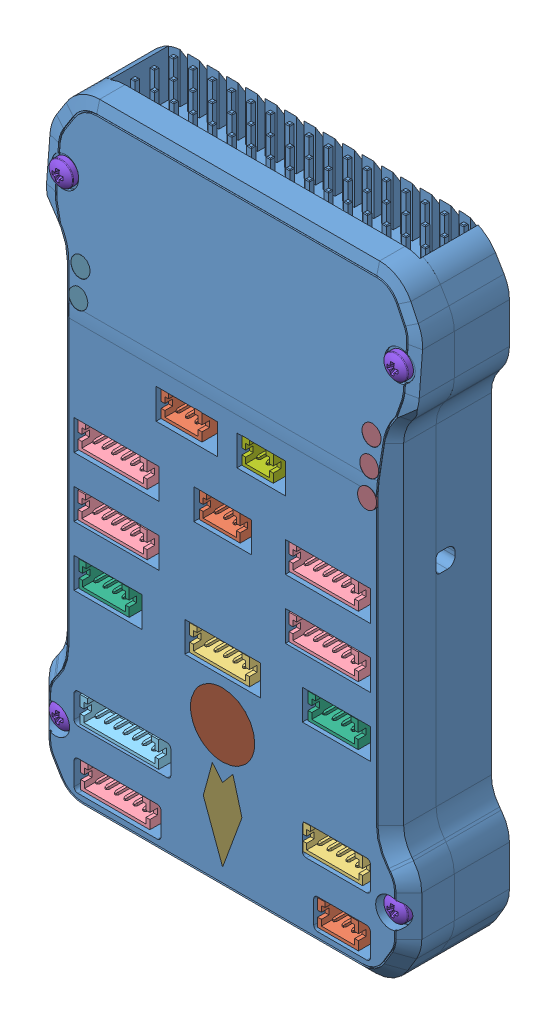
SolidWorks assembly Pixhawk, configuration Défaut. Lengths in mm.
Overall size (49.31 81.3 15.24).
26 component instances, 14 part files, 57 mates.
Components (placement in the parent):
- Pixhawk APM-1: Pixhawk APM [Défaut] at (-24.9203 -39.4022 0) size (49.31 81.3 15.03)
- DF13-3P-1.25DSA-1: DF13-3P-1.25DSA [Défaut] at (0.001 -60.127 12.2305) x (0 -1 0) z (-1 0 0) size (3.4 6.6 5.4)
- DF13-5P-1.25DSA-1: DF13-5P-1.25DSA [Défaut] at (0.5502 -52.3839 12.2305) x (0 -1 0) z (-1 0 0) size (3.4 6.6 7.9)
- DF13-6P-1.25DSA-1: DF13-6P-1.25DSA [Défaut] at (-27.5951 -60.0382 12.2305) x (0 -1 0) z (-1 0 0) size (3.4 6.6 9.15)
- DF13-7P-1.25DSA-1: DF13-7P-1.25DSA [Défaut] at (-26.4213 -52.538 12.2305) x (0 -1 0) z (-1 0 0) size (3.4 6.6 10.4)
- DF13-4P-1.25DSA-1: DF13-4P-1.25DSA [Défaut] at (-0.0265 -37.0823 12.2305) x (0 -1 0) z (-1 0 0) size (3.4 6.6 6.65)
- DF13-4P-1.25DSA-2: DF13-4P-1.25DSA [Défaut] at (-30.3382 -37.0823 12.2305) x (0 -1 0) z (-1 0 0) size (3.4 6.6 6.65)
- DF13-5P-1.25DSA-2: DF13-5P-1.25DSA [Défaut] at (-14.4216 -37.0823 12.2305) x (0 -1 0) z (-1 0 0) size (3.4 6.6 7.9)
- DF13-6P-1.25DSA-2: DF13-6P-1.25DSA [Défaut] at (-0.012 -29.2904 12.2305) x (0 -1 0) z (-1 0 0) size (3.4 6.6 9.15)
- DF13-6P-1.25DSA-3: DF13-6P-1.25DSA [Défaut] at (-0.012 -21.2194 12.2305) x (0 -1 0) z (-1 0 0) size (3.4 6.6 9.15)
- DF13-6P-1.25DSA-4: DF13-6P-1.25DSA [Défaut] at (-27.948 -29.2904 12.2305) x (0 -1 0) z (-1 0 0) size (3.4 6.6 9.15)
- DF13-6P-1.25DSA-5: DF13-6P-1.25DSA [Défaut] at (-27.948 -21.2194 12.2305) x (0 -1 0) z (-1 0 0) size (3.4 6.6 9.15)
- DF13-3P-1.25DSA-2: DF13-3P-1.25DSA [Défaut] at (-15.6441 -21.2194 12.2305) x (0 -1 0) z (-1 0 0) size (3.4 6.6 5.4)
- DF13-2P-1.25DSA-1: DF13-2P-1.25DSA [Défaut] at (-11.2684 -12.1811 12.2305) x (0 -1 0) z (-1 0 0) size (3.4 6.6 4.15)
- DF13-3P-1.25DSA-3: DF13-3P-1.25DSA [Défaut] at (-20.7011 -12.1811 12.2305) x (0 -1 0) z (-1 0 0) size (3.4 6.6 5.4)
- pan head cross recess screw_iso-1: pan head cross recess screw_iso [ISO 7045 - M1.6 x 3 - Z --- 3N] at (21.8797 32.2978 14.8) x (0 0 -1) z (1 0 0) size (4.27 3.2 3.2)
- pan head cross recess screw_iso-2: pan head cross recess screw_iso [ISO 7045 - M1.6 x 3 - Z --- 3N] at (-22.4203 32.2978 14.8) x (0 0 -1) z (1 0 0) size (4.27 3.2 3.2)
- pan head cross recess screw_iso-3: pan head cross recess screw_iso [ISO 7045 - M1.6 x 3 - Z --- 3N] at (21.8797 -29.8022 14.8) x (0 0 -1) z (1 0 0) size (4.27 3.2 3.2)
- pan head cross recess screw_iso-4: pan head cross recess screw_iso [ISO 7045 - M1.6 x 3 - Z --- 3N] at (-22.4203 -29.8022 14.8) x (0 0 -1) z (1 0 0) size (4.27 3.2 3.2)
- micro USB-2: micro USB [Défaut] at (-38.5288 4.0262 13.8589) x (0 1 0) z (-1 0 0) size (7.99 2.94 5.43)
  - micro usb02-1: micro usb02 [Défaut] at (-14.4796 6.4719 -20.7085) size (6.9 2.16 4.2)
  - micro USB-1: micro USB [Défaut] at (-14.4796 6.4719 -16.0085) size (7.99 2.94 5.43)
- pièce10^Pixhawk-1: pièce10^Pixhawk [Défaut] at (-24.9203 -39.4022 14.5) size (8.5 8.5 0.5) (virtual)
- pièce11^Pixhawk-1: pièce11^Pixhawk [Défaut] at (-24.9203 -39.4022 14.5) size (5.12 11.31 0.5) (virtual)
- Pièce12^Pixhawk-1: Pièce12^Pixhawk [Défaut] at (-24.9203 -37.8072 19.1403) x (1 0 0) z (0 0.083045 0.996546) size (2.5 9.53 0.5) (virtual)
- Pièce13^Pixhawk-1: Pièce13^Pixhawk [Défaut] at (-24.9203 -37.8072 19.1403) x (1 0 0) z (0 0.083045 0.996546) size (2.5 6.02 0.5) (virtual)
Mates (geometry in assembly coordinates):
- Coïncidente1: coincident aligned: plane of Pixhawk APM-1 through (-24.9203 -39.4022 15) normal (0 0 1); plane of DF13-3P-1.25DSA-1 through (18.451 -36.0098 15) normal (0 0 1)
- Parallèle1: parallel anti-aligned: plane of Pixhawk APM-1 through (19.2797 -36.8022 10) normal (0 1 0); plane of DF13-3P-1.25DSA-1 through (2.1962 -36.3098 14.6158) normal (0 -1 0)
- Coïncidente2: coincident aligned: plane of Pixhawk APM-1 through (-24.9203 -39.4022 15) normal (0 0 1); plane of DF13-5P-1.25DSA-1 through (10.8502 -25.8167 15) normal (0 0 1)
- Parallèle2: parallel anti-aligned: plane of Pixhawk APM-1 through (19.2797 -29.1022 10) normal (0 1 0); plane of DF13-5P-1.25DSA-1 through (15.2454 -28.5667 14.6158) normal (0 -1 0)
- Coïncidente4: coincident aligned: plane of Pixhawk APM-1 through (-24.9203 -39.4022 15) normal (0 0 1); plane of DF13-6P-1.25DSA-1 through (-18.5451 -33.471 15) normal (0 0 1)
- Parallèle3: parallel anti-aligned: plane of Pixhawk APM-1 through (-8.4203 -36.8022 10) normal (0 1 0); plane of DF13-6P-1.25DSA-1 through (-14.1499 -36.221 14.6158) normal (0 -1 0)
- Coïncidente5: coincident aligned: plane of Pixhawk APM-1 through (-24.9203 -39.4022 15) normal (0 0 1); plane of DF13-7P-1.25DSA-1 through (-22.9713 -28.4208 15) normal (0 0 1)
- Parallèle5: parallel anti-aligned: plane of Pixhawk APM-1 through (-7.1203 -29.1022 10) normal (0 1 0); plane of DF13-7P-1.25DSA-1 through (-24.2261 -28.7208 14.6158) normal (0 -1 0)
- Coïncidente6: coincident aligned: plane of Pixhawk APM-1 through (-24.9203 -39.4022 15) normal (0 0 1); plane of DF13-4P-1.25DSA-2 through (-26.8882 -12.9652 15) normal (0 0 1)
- Parallèle6: parallel anti-aligned: plane of Pixhawk APM-1 through (-10.9203 -13.8022 10) normal (0 1 0); plane of DF13-4P-1.25DSA-2 through (-14.393 -13.2652 14.6158) normal (0 -1 0)
- Coïncidente7: coincident aligned: plane of Pixhawk APM-1 through (-24.9203 -39.4022 15) normal (0 0 1); plane of DF13-4P-1.25DSA-1 through (3.4235 -12.9652 15) normal (0 0 1)
- Coïncidente8: coincident aligned: plane of DF13-4P-1.25DSA-1 through (15.9187 -13.2652 14.6158) normal (0 -1 0); plane of DF13-4P-1.25DSA-2 through (-14.393 -13.2652 14.6158) normal (0 -1 0)
- Coïncidente9: coincident aligned: plane of Pixhawk APM-1 through (-24.9203 -39.4022 15) normal (0 0 1); plane of DF13-5P-1.25DSA-2 through (-10.9716 -12.9652 15) normal (0 0 1)
- Coïncidente10: coincident aligned: plane of DF13-4P-1.25DSA-2 through (-14.393 -13.2652 14.6158) normal (0 -1 0); plane of DF13-5P-1.25DSA-2 through (0.2736 -13.2652 14.6158) normal (0 -1 0)
- Coïncidente12: coincident aligned: plane of Pixhawk APM-1 through (-24.9203 -39.4022 15) normal (0 0 1); plane of DF13-6P-1.25DSA-2 through (3.438 -5.1732 15) normal (0 0 1)
- Parallèle8: parallel anti-aligned: plane of Pixhawk APM-1 through (19.2797 -5.9022 10) normal (0 1 0); plane of DF13-6P-1.25DSA-2 through (13.4332 -5.4732 14.6158) normal (0 -1 0)
- Coïncidente13: coincident: plane of DF13-6P-1.25DSA-2 through (3.438 -5.1732 15) normal (0 0 1); plane of DF13-6P-1.25DSA-3 through (3.438 2.8978 15) normal (0 0 1)
- Coïncidente14: coincident aligned: plane of DF13-6P-1.25DSA-2 through (17.688 -3.9719 9.9583) normal (1 0 0); plane of DF13-6P-1.25DSA-3 through (17.688 4.0991 9.9583) normal (1 0 0)
- Coïncidente15: coincident aligned: plane of Pixhawk APM-1 through (-24.9203 -39.4022 15) normal (0 0 1); plane of DF13-6P-1.25DSA-4 through (-18.898 -2.7232 15) normal (0 0 1)
- Coïncidente16: coincident aligned: plane of DF13-6P-1.25DSA-2 through (13.4332 -5.4732 14.6158) normal (0 -1 0); plane of DF13-6P-1.25DSA-4 through (-14.5028 -5.4732 14.6158) normal (0 -1 0)
- Coïncidente17: coincident aligned: plane of Pixhawk APM-1 through (-24.9203 -39.4022 15) normal (0 0 1); plane of DF13-6P-1.25DSA-5 through (-18.898 5.3478 15) normal (0 0 1)
- Coïncidente18: coincident aligned: plane of DF13-6P-1.25DSA-3 through (13.4332 2.5978 14.6158) normal (0 -1 0); plane of DF13-6P-1.25DSA-5 through (-14.5028 2.5978 14.6158) normal (0 -1 0)
- Coïncidente19: coincident aligned: plane of DF13-6P-1.25DSA-4 through (-10.248 -3.9719 9.9583) normal (1 0 0); plane of DF13-6P-1.25DSA-5 through (-10.248 4.0991 9.9583) normal (1 0 0)
- Coïncidente20: coincident aligned: plane of Pixhawk APM-1 through (-24.9203 -39.4022 15) normal (0 0 1); plane of DF13-3P-1.25DSA-2 through (-2.8441 5.3478 15) normal (0 0 1)
- Coïncidente21: coincident aligned: plane of DF13-6P-1.25DSA-3 through (13.4332 2.5978 14.6158) normal (0 -1 0); plane of DF13-3P-1.25DSA-2 through (-13.4489 2.5978 14.6158) normal (0 -1 0)
- Coïncidente22: coincident aligned: plane of Pixhawk APM-1 through (-24.9203 -39.4022 15) normal (0 0 1); plane of DF13-2P-1.25DSA-1 through (2.7816 14.386 15) normal (0 0 1)
- Parallèle9: parallel anti-aligned: plane of Pixhawk APM-1 through (8.0297 10.9978 10) normal (0 1 0); plane of DF13-2P-1.25DSA-1 through (-9.0732 11.636 14.6158) normal (0 -1 0)
- Coïncidente23: coincident aligned: plane of Pixhawk APM-1 through (-24.9203 -39.4022 15) normal (0 0 1); plane of DF13-3P-1.25DSA-3 through (-7.9011 14.386 15) normal (0 0 1)
- Coïncidente24: coincident aligned: plane of DF13-2P-1.25DSA-1 through (-9.0732 11.636 14.6158) normal (0 -1 0); plane of DF13-3P-1.25DSA-3 through (-18.5059 11.636 14.6158) normal (0 -1 0)
- Coaxiale2: concentric aligned: cylinder of Pixhawk APM-1 through (21.8797 32.2978 7.5) axis (0 0 1) radius 1; line of pan head cross recess screw_iso-1 through (21.8797 32.2978 40.2) axis (0 0 1)
- Coïncidente25: coincident anti-aligned: plane of Pixhawk APM-1 through (21.8797 32.2978 13.5) normal (0 0 1); plane of pan head cross recess screw_iso-1 through (21.8797 33.0978 13.5) normal (0 0 -1)
- Coaxiale3: concentric aligned: cylinder of Pixhawk APM-1 through (-22.4203 32.2978 7.5) axis (0 0 1) radius 1; cylinder of pan head cross recess screw_iso-2 through (-22.4203 32.2978 40.2) axis (0 0 1) radius 1.6
- Coïncidente26: coincident anti-aligned: plane of Pixhawk APM-1 through (-22.4203 32.2978 13.5) normal (0 0 1); plane of pan head cross recess screw_iso-2 through (-22.4203 33.0978 13.5) normal (0 0 -1)
- Coaxiale4: concentric aligned: cylinder of Pixhawk APM-1 through (21.8797 -29.8022 7.5) axis (0 0 1) radius 1; cylinder of pan head cross recess screw_iso-3 through (21.8797 -29.8022 40.2) axis (0 0 1) radius 1.6
- Coïncidente27: coincident anti-aligned: plane of Pixhawk APM-1 through (21.8797 -29.8022 13.5) normal (0 0 1); plane of pan head cross recess screw_iso-3 through (21.8797 -29.0022 13.5) normal (0 0 -1)
- Coaxiale5: concentric aligned: cylinder of Pixhawk APM-1 through (-22.4203 -29.8022 7.5) axis (0 0 1) radius 1; cylinder of pan head cross recess screw_iso-4 through (-22.4203 -29.8022 40.2) axis (0 0 1) radius 1.6
- Coïncidente28: coincident anti-aligned: plane of Pixhawk APM-1 through (-22.4203 -29.8022 13.5) normal (0 0 1); plane of pan head cross recess screw_iso-4 through (-22.4203 -29.0022 13.5) normal (0 0 -1)
- Parallèle10: parallel aligned: plane of Pixhawk APM-1 through (-16.5203 -6.5322 5.66) normal (0 0 1); plane of micro USB-2/micro USB-1 through (-17.8203 -13.6535 6.162) normal (0 0 1)
- Parallèle11: parallel anti-aligned: line of Pixhawk APM-1 through (-22.5203 -7.0322 5.66) axis (0 -1 0); line of micro USB-2/micro USB-1 through (-22.944 -13.4535 6.1119) axis (0 1 0)
- Sur place1: in place: plane of ? through (-0.7222 -19.1501 14.5) normal (0 0 1); plane of ? through (0 0 14.5) normal (0 0 1); moOrthogonalPlaneRef_w of ? through (-0.7222 -19.1501 14.5) normal (0 0 1); plane of ? through (0 0 14.5) normal (0 1 0); plane of ? through (-0.7222 -19.1501 14.5) normal (0 0 1); plane of ? through (0 0 14.5) normal (1 0 0); plane of Pixhawk APM-1 through (-0.2703 -19.4022 14.5) normal (0 0 1); unknown of ?
- Coïncidente29: coincident aligned: 
- Coïncidente30: coincident aligned: plane of Pixhawk APM-1 through (-24.9203 -39.4022 14.5) normal (0 1 0); plane of ? through (-24.9203 -39.4022 14.5) normal (0 1 0)
- Coïncidente31: coincident anti-aligned: plane of Pixhawk APM-1 through (-24.9203 -39.4022 14.5) normal (-1 0 0); plane of ? through (-24.9203 -39.4022 14.5) normal (1 0 0)
- Sur place2: in place: plane of ? through (-25.3722 -39.1501 14.5) normal (0 0 1); plane of ? through (0 0 14.5) normal (0 0 1); plane of ? through (-25.3722 -39.1501 14.5) normal (0 0 1); plane of ? through (0 0 14.5) normal (0 1 0); plane of ? through (-25.3722 -39.1501 14.5) normal (0 0 1); plane of ? through (0 0 14.5) normal (1 0 0); plane of Pixhawk APM-1 through (-24.9203 -39.4022 14.5) normal (0 0 1); unknown of ?
- Coïncidente32: coincident aligned: 
- Coïncidente33: coincident aligned: plane of Pixhawk APM-1 through (-24.9203 -39.4022 14.5) normal (0 1 0); plane of ? through (-24.9203 -39.4022 14.5) normal (0 1 0)
- Coïncidente34: coincident anti-aligned: plane of Pixhawk APM-1 through (-24.9203 -39.4022 14.5) normal (-1 0 0); plane of ? through (-24.9203 -39.4022 14.5) normal (1 0 0)
- Sur place3: in place: plane of ? through (-25.3722 18.1083 14.5017) normal (0 0.083045 0.996546); plane of ? through (0 1.325 15.9003) normal (0 0.083045 0.996546); plane of ? through (-25.3722 18.1083 14.5017) normal (0 0.083045 0.996546); plane of ? through (0 1.325 15.9003) normal (0 0.996546 -0.083045); plane of ? through (-25.3722 18.1083 14.5017) normal (0 0.083045 0.996546); unknown of ?; plane of Pixhawk APM-1 through (-24.9203 17.8563 14.5017) normal (0 0.083045 0.996546); unknown of ?
- Coïncidente35: coincident aligned: 
- Coïncidente36: coincident aligned: plane of Pixhawk APM-1 through (-24.9203 -37.8072 19.1403) normal (0 0.996546 -0.083045); plane of ? through (-24.9203 -37.8072 19.1403) normal (0 0.996546 -0.083045)
- Coïncidente37: coincident anti-aligned: plane of Pixhawk APM-1 through (-24.9203 -37.8072 19.1403) normal (-1 0 0); unknown of ?
- Sur place4: in place: plane of ? through (-25.3722 18.1083 14.5017) normal (0 0.083045 0.996546); plane of ? through (0 1.325 15.9003) normal (0 0.083045 0.996546); plane of ? through (-25.3722 18.1083 14.5017) normal (0 0.083045 0.996546); plane of ? through (0 1.325 15.9003) normal (0 0.996546 -0.083045); plane of ? through (-25.3722 18.1083 14.5017) normal (0 0.083045 0.996546); unknown of ?; plane of Pixhawk APM-1 through (-24.9203 17.8563 14.5017) normal (0 0.083045 0.996546); unknown of ?
- Coïncidente38: coincident aligned: 
- Coïncidente39: coincident aligned: plane of Pixhawk APM-1 through (-24.9203 -37.8072 19.1403) normal (0 0.996546 -0.083045); plane of ? through (-24.9203 -37.8072 19.1403) normal (0 0.996546 -0.083045)
- Coïncidente40: coincident anti-aligned: plane of Pixhawk APM-1 through (-24.9203 -37.8072 19.1403) normal (-1 0 0); unknown of ?
- Coincident1: coincident anti-aligned: plane of micro USB-2/micro USB-1 through (-22.5203 -13.6535 6.712) normal (1 0 0); plane of Pixhawk APM-1 through (-22.5203 24.8978 15) normal (-1 0 0)
- Coincident2: coincident: plane of Pixhawk APM-1 through (-8.6703 5.9978 10) normal (0 -1 0); line of DF13-6P-1.25DSA-5 through (-10.248 5.9978 10.7) axis (-1 0 0)
